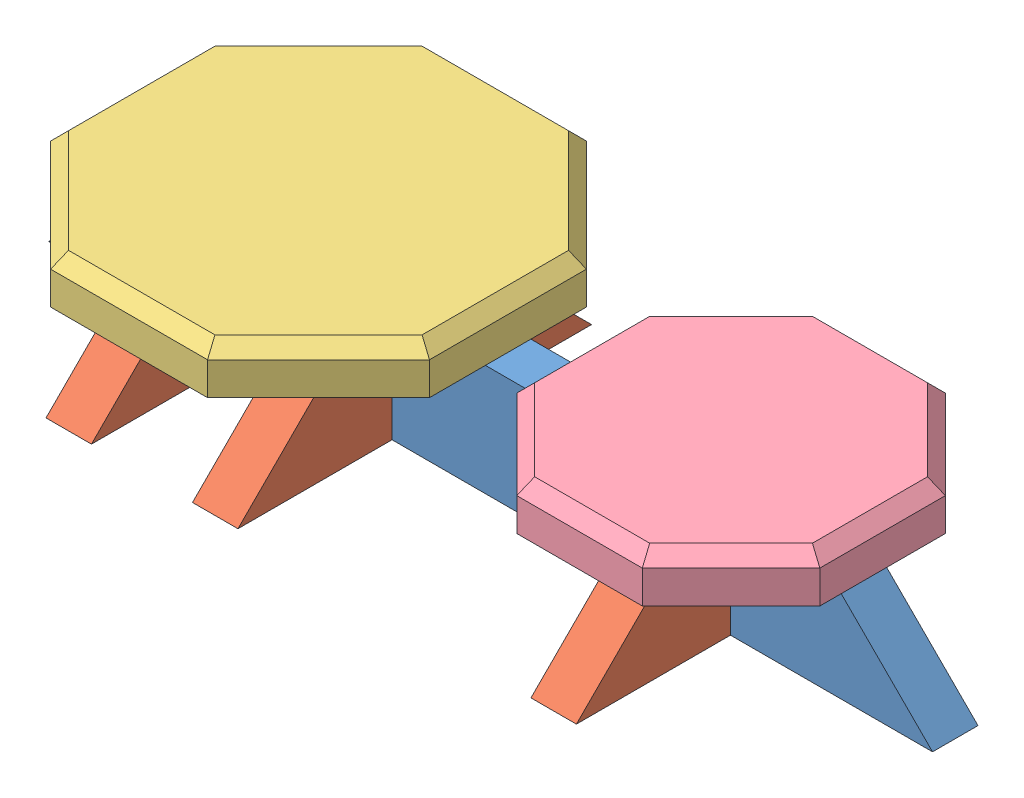
SolidWorks assembly Teapot Stand, configuration Default. Lengths in mm.
Overall size (350 62 150).
6 component instances, 4 part files, 2 mates.
Components (placement in the parent):
- Base Piece-1: Base Piece [Default] at (-13.4072 5.5325 3.3161) size (350 44 18)
- Support-1: Support [Default] at (-119.4072 5.5325 3.3161) x (0 0 -1) z (1 0 0) size (140 44 18)
- Support-2: Support [Default] at (-61.4072 5.5325 3.3161) x (0 0 -1) z (1 0 0) size (140 44 18)
- Support-3: Support [Default] at (72.5928 5.5325 3.3161) x (0 0 -1) z (1 0 0) size (140 44 18)
- Large Top-1: Large Top [Default] at (-90.4316 36.5325 3.3992) size (150 18 150)
- Small Top-1: Small Top [Default] at (73.2737 36.5325 3.7616) size (120 18 120)
Mates (geometry in assembly coordinates):
- Coincident11: coincident anti-aligned: plane of Base Piece-1 through (-144.4072 27.5325 12.3161) normal (0 1 0); plane of Large Top-1 through (-165.4316 27.5325 -71.6008) normal (0 -1 0)
- Coincident13: coincident anti-aligned: plane of Base Piece-1 through (-144.4072 27.5325 12.3161) normal (0 1 0); plane of Small Top-1 through (13.2737 27.5325 -56.2384) normal (0 -1 0)
